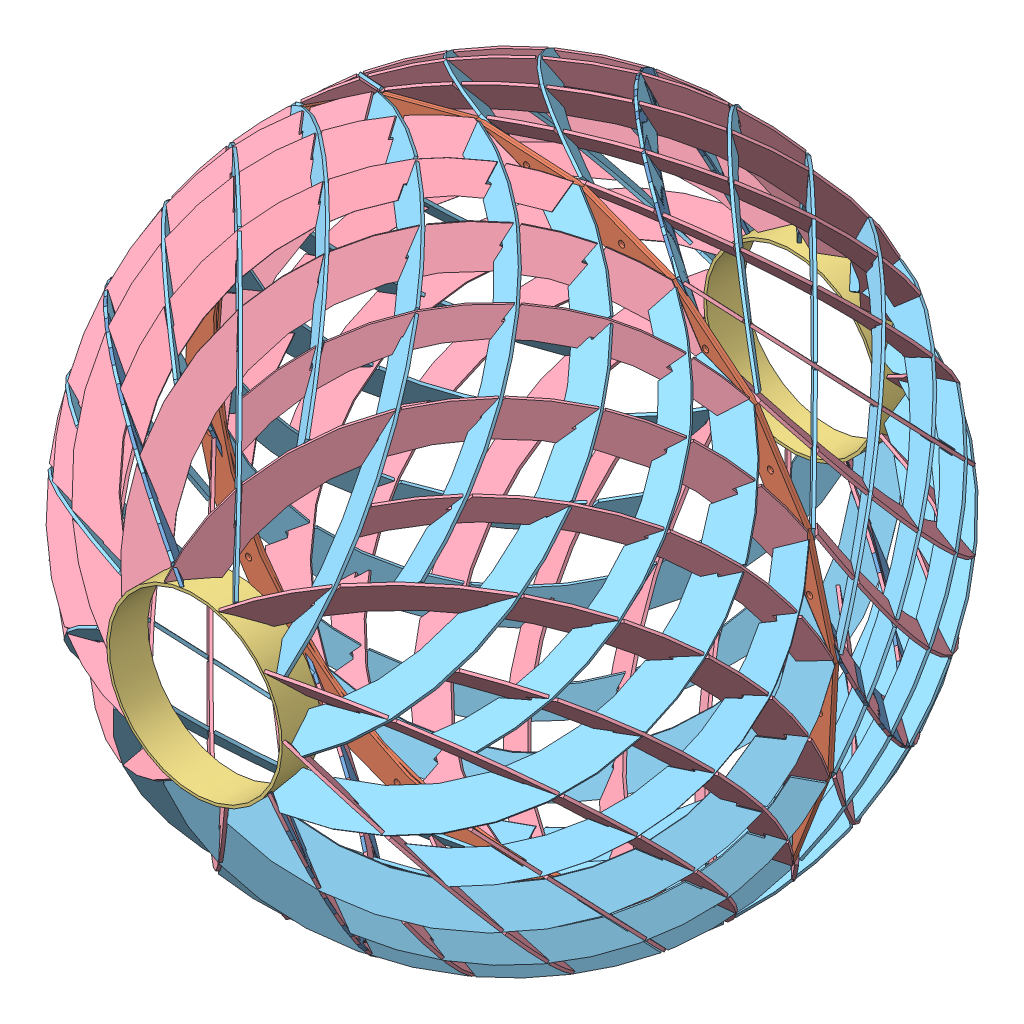
SolidWorks assembly whole_shell, configuration Default. Lengths in mm.
Overall size (1237.57 1237.01 762).
90 component instances, 6 part files, 5 mates.
Components (placement in the parent):
- frame1-1: frame1 [Default] x (0.840513 0.541791 0) z (-0.541791 0.840513 0) size (896.02 758.6 894.17)
  - sphere_outline-1: sphere_outline [Default] at origin size (762 758.6 762) (hidden)
  - rib-1: rib [Default] x (-1 0 0) z (0 1 0) size (381.83 596.96 365.18)
  - waist-1: waist [Default] x (-1 0 0) z (0 1 0) size (743.4 741.73 3.17)
  - axle_frame-1: axle_frame [Default] at (0 -6.0987 0) x (-1 0 0) z (0 1 0) size (203.2 203.2 44.45)
  - inside_rib-1: inside_rib [Default] x (1 0 0) z (0 1 0) size (379.15 205.09 365.17)
  - outside_rib-1: outside_rib [Default] x (1 0 0) z (0 1 0) size (373.79 201.22 360.01)
  - outside_rib-2: outside_rib [Default] x (0.809017 0 -0.587785) z (0 1 0) size (373.79 201.22 360.01)
  - outside_rib-3: outside_rib [Default] x (0.309017 0 -0.951057) z (0 1 0) size (373.79 201.22 360.01)
  - outside_rib-4: outside_rib [Default] x (-0.309017 0 -0.951057) z (0 1 0) size (373.79 201.22 360.01)
  - outside_rib-5: outside_rib [Default] x (-0.809017 0 -0.587785) z (0 1 0) size (373.79 201.22 360.01)
  - outside_rib-6: outside_rib [Default] x (-1 0 0) z (0 1 0) size (373.79 201.22 360.01)
  - outside_rib-7: outside_rib [Default] x (-0.809017 0 0.587785) z (0 1 0) size (373.79 201.22 360.01)
  - outside_rib-8: outside_rib [Default] x (-0.309017 0 0.951057) z (0 1 0) size (373.79 201.22 360.01)
  - outside_rib-9: outside_rib [Default] x (0.309017 0 0.951057) z (0 1 0) size (373.79 201.22 360.01)
  - inside_rib-2: inside_rib [Default] x (0.809017 0 -0.587785) z (0 1 0) size (379.15 205.09 365.17)
  - inside_rib-3: inside_rib [Default] x (0.309017 0 -0.951057) z (0 1 0) size (379.15 205.09 365.17)
  - inside_rib-4: inside_rib [Default] x (-0.309017 0 -0.951057) z (0 1 0) size (379.15 205.09 365.17)
  - inside_rib-5: inside_rib [Default] x (-0.809017 0 -0.587785) z (0 1 0) size (379.15 205.09 365.17)
  - inside_rib-6: inside_rib [Default] x (-1 0 0) z (0 1 0) size (379.15 205.09 365.17)
  - inside_rib-7: inside_rib [Default] x (-0.809017 0 0.587785) z (0 1 0) size (379.15 205.09 365.17)
  - inside_rib-8: inside_rib [Default] x (-0.309017 0 0.951057) z (0 1 0) size (379.15 205.09 365.17)
  - inside_rib-9: inside_rib [Default] x (0.309017 0 0.951057) z (0 1 0) size (379.15 205.09 365.17)
  - outside_rib-10: outside_rib [Default] x (0.809017 0 0.587785) z (0 1 0) size (373.79 201.22 360.01)
  - inside_rib-10: inside_rib [Default] x (0.809017 0 0.587785) z (0 1 0) size (379.15 205.09 365.17)
  - inside_rib-21: inside_rib [short] x (0.951057 0 -0.309017) z (0 1 0) size (304.88 133.31 293.67)
  - inside_rib-22: inside_rib [short] x (0.587785 0 -0.809017) z (0 1 0) size (304.88 133.31 293.67)
  - inside_rib-23: inside_rib [short] x (0 0 -1) z (0 1 0) size (304.88 133.31 293.67)
  - inside_rib-24: inside_rib [short] x (-0.587785 0 -0.809017) z (0 1 0) size (304.88 133.31 293.67)
  - inside_rib-25: inside_rib [short] x (-0.951057 0 -0.309017) z (0 1 0) size (304.88 133.31 293.67)
  - inside_rib-26: inside_rib [short] x (-0.951057 0 0.309017) z (0 1 0) size (304.88 133.31 293.67)
  - inside_rib-27: inside_rib [short] x (-0.587785 0 0.809017) z (0 1 0) size (304.88 133.31 293.67)
  - inside_rib-28: inside_rib [short] x (0 0 1) z (0 1 0) size (304.88 133.31 293.67)
  - inside_rib-29: inside_rib [short] x (0.587785 0 0.809017) z (0 1 0) size (304.88 133.31 293.67)
  - inside_rib-30: inside_rib [short] x (0.951057 0 0.309017) z (0 1 0) size (304.88 133.31 293.67)
  - outside_rib-21: outside_rib [short] x (0.951057 0 -0.309017) z (0 1 0) size (304.88 133.31 293.67)
  - outside_rib-22: outside_rib [short] x (0.587785 0 -0.809017) z (0 1 0) size (304.88 133.31 293.67)
  - outside_rib-23: outside_rib [short] x (0 0 -1) z (0 1 0) size (304.88 133.31 293.67)
  - outside_rib-24: outside_rib [short] x (-0.587785 0 -0.809017) z (0 1 0) size (304.88 133.31 293.67)
  - outside_rib-25: outside_rib [short] x (-0.951057 0 -0.309017) z (0 1 0) size (304.88 133.31 293.67)
  - outside_rib-26: outside_rib [short] x (-0.951057 0 0.309017) z (0 1 0) size (304.88 133.31 293.67)
  - outside_rib-27: outside_rib [short] x (-0.587785 0 0.809017) z (0 1 0) size (304.88 133.31 293.67)
  - outside_rib-28: outside_rib [short] x (0 0 1) z (0 1 0) size (304.88 133.31 293.67)
  - outside_rib-29: outside_rib [short] x (0.587785 0 0.809017) z (0 1 0) size (304.88 133.31 293.67)
  - outside_rib-30: outside_rib [short] x (0.951057 0 0.309017) z (0 1 0) size (304.88 133.31 293.67)
- frame1-2: frame1 [Default] x (-0.840513 -0.541791 0) z (-0.541791 0.840513 0) size (896.02 758.6 894.17)
  - sphere_outline-1: sphere_outline [Default] at origin size (762 758.6 762) (hidden)
  - rib-1: rib [Default] x (-1 0 0) z (0 1 0) size (381.83 596.96 365.18)
  - waist-1: waist [Default] x (-1 0 0) z (0 1 0) size (743.4 741.73 3.17)
  - axle_frame-1: axle_frame [Default] at (0 -6.0987 0) x (-1 0 0) z (0 1 0) size (203.2 203.2 44.45)
  - inside_rib-1: inside_rib [Default] x (1 0 0) z (0 1 0) size (379.15 205.09 365.17)
  - outside_rib-1: outside_rib [Default] x (1 0 0) z (0 1 0) size (373.79 201.22 360.01)
  - outside_rib-2: outside_rib [Default] x (0.809017 0 -0.587785) z (0 1 0) size (373.79 201.22 360.01)
  - outside_rib-3: outside_rib [Default] x (0.309017 0 -0.951057) z (0 1 0) size (373.79 201.22 360.01)
  - outside_rib-4: outside_rib [Default] x (-0.309017 0 -0.951057) z (0 1 0) size (373.79 201.22 360.01)
  - outside_rib-5: outside_rib [Default] x (-0.809017 0 -0.587785) z (0 1 0) size (373.79 201.22 360.01)
  - outside_rib-6: outside_rib [Default] x (-1 0 0) z (0 1 0) size (373.79 201.22 360.01)
  - outside_rib-7: outside_rib [Default] x (-0.809017 0 0.587785) z (0 1 0) size (373.79 201.22 360.01)
  - outside_rib-8: outside_rib [Default] x (-0.309017 0 0.951057) z (0 1 0) size (373.79 201.22 360.01)
  - outside_rib-9: outside_rib [Default] x (0.309017 0 0.951057) z (0 1 0) size (373.79 201.22 360.01)
  - inside_rib-2: inside_rib [Default] x (0.809017 0 -0.587785) z (0 1 0) size (379.15 205.09 365.17)
  - inside_rib-3: inside_rib [Default] x (0.309017 0 -0.951057) z (0 1 0) size (379.15 205.09 365.17)
  - inside_rib-4: inside_rib [Default] x (-0.309017 0 -0.951057) z (0 1 0) size (379.15 205.09 365.17)
  - inside_rib-5: inside_rib [Default] x (-0.809017 0 -0.587785) z (0 1 0) size (379.15 205.09 365.17)
  - inside_rib-6: inside_rib [Default] x (-1 0 0) z (0 1 0) size (379.15 205.09 365.17)
  - inside_rib-7: inside_rib [Default] x (-0.809017 0 0.587785) z (0 1 0) size (379.15 205.09 365.17)
  - inside_rib-8: inside_rib [Default] x (-0.309017 0 0.951057) z (0 1 0) size (379.15 205.09 365.17)
  - inside_rib-9: inside_rib [Default] x (0.309017 0 0.951057) z (0 1 0) size (379.15 205.09 365.17)
  - outside_rib-10: outside_rib [Default] x (0.809017 0 0.587785) z (0 1 0) size (373.79 201.22 360.01)
  - inside_rib-10: inside_rib [Default] x (0.809017 0 0.587785) z (0 1 0) size (379.15 205.09 365.17)
  - inside_rib-21: inside_rib [short] x (0.951057 0 -0.309017) z (0 1 0) size (304.88 133.31 293.67)
  - inside_rib-22: inside_rib [short] x (0.587785 0 -0.809017) z (0 1 0) size (304.88 133.31 293.67)
  - inside_rib-23: inside_rib [short] x (0 0 -1) z (0 1 0) size (304.88 133.31 293.67)
  - inside_rib-24: inside_rib [short] x (-0.587785 0 -0.809017) z (0 1 0) size (304.88 133.31 293.67)
  - inside_rib-25: inside_rib [short] x (-0.951057 0 -0.309017) z (0 1 0) size (304.88 133.31 293.67)
  - inside_rib-26: inside_rib [short] x (-0.951057 0 0.309017) z (0 1 0) size (304.88 133.31 293.67)
  - inside_rib-27: inside_rib [short] x (-0.587785 0 0.809017) z (0 1 0) size (304.88 133.31 293.67)
  - inside_rib-28: inside_rib [short] x (0 0 1) z (0 1 0) size (304.88 133.31 293.67)
  - inside_rib-29: inside_rib [short] x (0.587785 0 0.809017) z (0 1 0) size (304.88 133.31 293.67)
  - inside_rib-30: inside_rib [short] x (0.951057 0 0.309017) z (0 1 0) size (304.88 133.31 293.67)
  - outside_rib-21: outside_rib [short] x (0.951057 0 -0.309017) z (0 1 0) size (304.88 133.31 293.67)
  - outside_rib-22: outside_rib [short] x (0.587785 0 -0.809017) z (0 1 0) size (304.88 133.31 293.67)
  - outside_rib-23: outside_rib [short] x (0 0 -1) z (0 1 0) size (304.88 133.31 293.67)
  - outside_rib-24: outside_rib [short] x (-0.587785 0 -0.809017) z (0 1 0) size (304.88 133.31 293.67)
  - outside_rib-25: outside_rib [short] x (-0.951057 0 -0.309017) z (0 1 0) size (304.88 133.31 293.67)
  - outside_rib-26: outside_rib [short] x (-0.951057 0 0.309017) z (0 1 0) size (304.88 133.31 293.67)
  - outside_rib-27: outside_rib [short] x (-0.587785 0 0.809017) z (0 1 0) size (304.88 133.31 293.67)
  - outside_rib-28: outside_rib [short] x (0 0 1) z (0 1 0) size (304.88 133.31 293.67)
  - outside_rib-29: outside_rib [short] x (0.587785 0 0.809017) z (0 1 0) size (304.88 133.31 293.67)
  - outside_rib-30: outside_rib [short] x (0.951057 0 0.309017) z (0 1 0) size (304.88 133.31 293.67)
Mates (geometry in assembly coordinates):
- Coincident3: coincident anti-aligned: plane of ? through (0 0 0) normal (0 0 1); plane of ? through (0 0 0) normal (0 0 -1)
- Coincident4: coincident aligned: plane of frame1-1/sphere_outline-1 through (0 0 0) normal (-0.541791 0.840513 0); plane of frame1-2/sphere_outline-1 through (0 0 0) normal (-0.541791 0.840513 0)
- Coincident6: coincident anti-aligned: unknown of frame1-1/sphere_outline-1
- Concentric1: concentric aligned: unknown of frame1-2/axle_frame-1
- Concentric2: concentric anti-aligned: unknown of frame1-1/axle_frame-1
